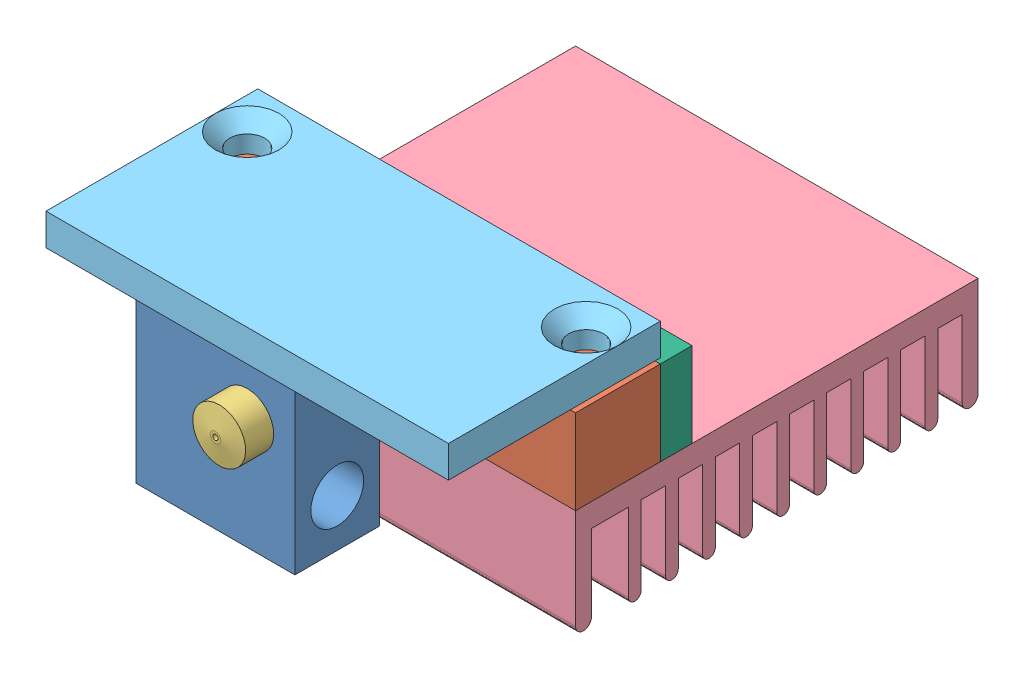
SolidWorks assembly extruder-nozzle-assy 00, configuration Default. Lengths in mm.
Overall size (38 21.7 53).
6 component instances, 6 part files, 14 mates.
Components (placement in the parent):
- heater-block 00-1: heater-block 00 [Default] at (-5.288 -2.2669 4.3305) size (15 15 8)
- heatsink-block 00-1: heatsink-block 00 [Default] at (24.212 12.2331 0.3305) x (-1 0 0) z (0 -1 0) size (38 8 8)
- nozzle 00-1: nozzle 00 [Default] at (5.212 8.2331 15.3305) x (0.923728 0.383049 0) z (0 0 -1) size (5 5 27)
- heatsink-1: heatsink [Default] at (24.212 4.2331 -18.6695) x (0 0 -1) z (-1 0 0) size (38 10.2 38)
- heat-shield 00-1: heat-shield 00 [Default] at (5.212 12.7331 12.3305) x (1 0 0) z (0 1 0) size (38 20 3)
- heat-spacer 00-1: heat-spacer 00 [Default] at (5.212 4.2331 -7.6695) x (-1 0 0) z (0 0 -1) size (38 8 3)
Mates (geometry in assembly coordinates):
- Concentric1: concentric aligned: cylinder of heater-block 00-1 through (5.212 8.2331 12.3305) axis (0 0 1) radius 2.1; cylinder of nozzle 00-1 through (5.212 8.2331 -11.6695) axis (0 0 1) radius 2.5
- Distance1: distance = 3 mm aligned: plane of nozzle 00-1 through (5.212 8.2331 15.3305) normal (0 0 1); plane of heater-block 00-1 through (-5.288 12.7331 12.3305) normal (0 0 1)
- Concentric2: concentric anti-aligned: cylinder of heatsink-block 00-1 through (5.212 8.2331 -7.6695) axis (0 0 -1) radius 2.1; cylinder of nozzle 00-1 through (5.212 8.2331 -11.6695) axis (0 0 1) radius 2.5
- Distance2: distance = 4 mm anti-aligned: plane of heatsink-block 00-1 through (24.212 4.2331 0.3305) normal (0 0 1); plane of heater-block 00-1 through (-5.288 12.7331 4.3305) normal (0 0 -1)
- Parallel1: parallel aligned: plane of heater-block 00-1 through (-5.288 12.7331 12.3305) normal (0 1 0); plane of heatsink-block 00-1 through (24.212 12.2331 -7.6695) normal (0 1 0)
- Coincident5: coincident anti-aligned: plane of heatsink-block 00-1 through (24.212 4.2331 -7.6695) normal (0 -1 0); plane of heatsink-1 through (-13.788 4.2331 0.3305) normal (0 1 0)
- Coincident6: coincident aligned: plane of heatsink-block 00-1 through (24.212 4.2331 0.3305) normal (0 0 1); plane of heatsink-1 through (-13.788 2.0331 0.3305) normal (0 0 1)
- Coincident9: coincident aligned: plane of heatsink-block 00-1 through (-13.788 4.2331 0.3305) normal (-1 0 0); plane of heatsink-1 through (-13.788 -5.2169 -0.4195) normal (-1 0 0)
- Concentric3: concentric aligned: cylinder of heatsink-block 00-1 through (21.212 12.2331 -3.6695) axis (0 1 0) radius 1.25; cylinder of heat-shield 00-1 through (21.212 15.7331 -3.6695) axis (0 1 0) radius 1.65
- Concentric4: concentric aligned: cylinder of heatsink-block 00-1 through (-10.788 12.2331 -3.6695) axis (0 1 0) radius 1.25; cylinder of heat-shield 00-1 through (-10.788 15.7331 -3.6695) axis (0 1 0) radius 1.65
- Distance4: distance = 0.5 mm anti-aligned: plane of heatsink-block 00-1 through (24.212 12.2331 -7.6695) normal (0 1 0); plane of heat-shield 00-1 through (-13.788 12.7331 -7.6695) normal (0 -1 0)
- Coincident10: coincident anti-aligned: plane of heatsink-block 00-1 through (24.212 4.2331 -7.6695) normal (0 0 -1); plane of heat-spacer 00-1 through (24.212 12.2331 -7.6695) normal (0 0 1)
- Concentric5: concentric anti-aligned: cylinder of nozzle 00-1 through (5.212 8.2331 -11.6695) axis (0 0 1) radius 2.5; cylinder of heat-spacer 00-1 through (5.212 8.2331 -7.6695) axis (0 0 -1) radius 2.65
- Parallel2: parallel aligned: plane of heatsink-block 00-1 through (24.212 12.2331 -7.6695) normal (0 1 0); plane of heat-spacer 00-1 through (24.212 12.2331 -10.6695) normal (0 1 0)
